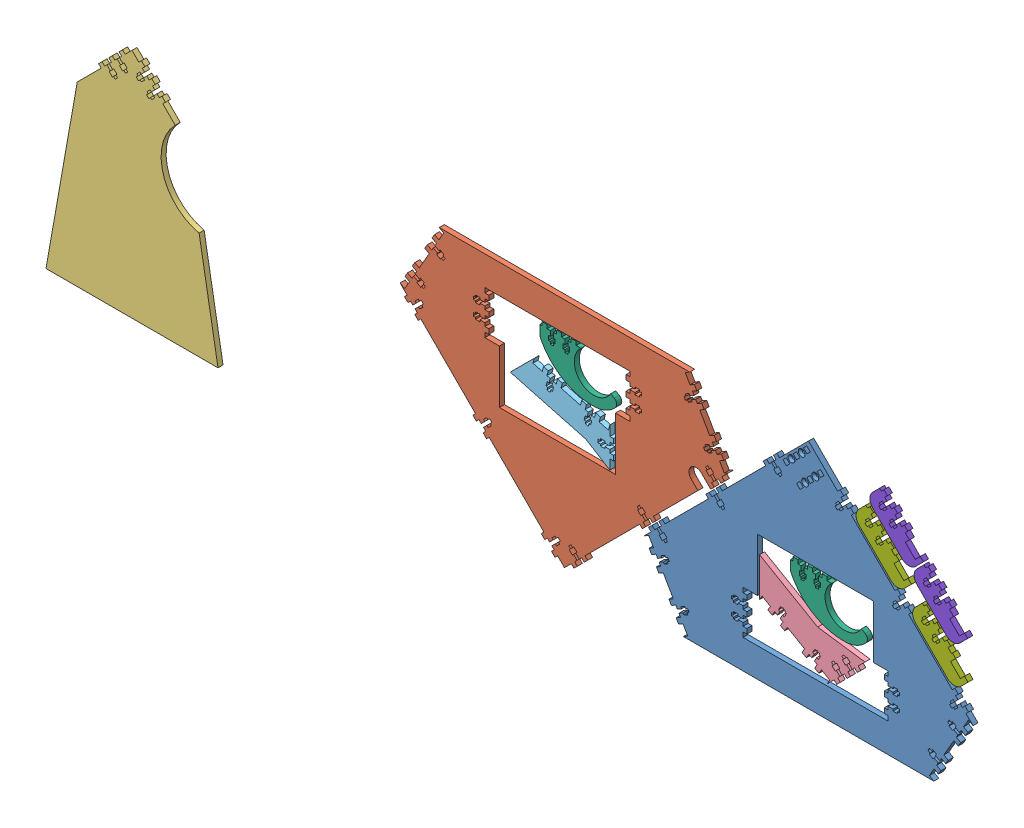
SolidWorks assembly Acrylic_1, configuration Default. Lengths in mm.
Overall size (1219.2 304.8 6.6).
11 component instances, 8 part files, 31 mates.
Components (placement in the parent):
- RIB 1, FRAME-1: RIB 1, FRAME [LASER CUT] at (-137.0148 0.0508 0) size (431.67 304.55 6.6)
- RIB 2, FRAME-1: RIB 2, FRAME [LASER CUT] at (-457.4769 304.7492 0) x (-1 0 0) z (0 0 1) size (431.67 304.55 6.6)
- RIB 3, FRAME-1: RIB 3, FRAME [LASER CUT] at (-1025.2225 0.0508 0) size (225.83 304.55 6.6)
- RIB 4 INFEED, FRAME-1: RIB 4 INFEED, FRAME [LASER CUT] at (-201.3286 256.3325 0) x (0 -1 0) z (0 0 1) size (102.28 138.45 6.6)
- RIB 4 OUTFEED, FRAME-1: RIB 4 OUTFEED, FRAME [LASER CUT] at (-613.2509 102.3228 0) x (-0.707107 -0.707107 0) z (0 0 1) size (96.17 124.97 6.6)
- BRACKET, VACUUM TUBE-1: BRACKET, VACUUM TUBE [LASER CUT] at (-435.898 265.5316 0) size (101.09 62.36 6.6)
- BRACKET, VACUUM TUBE-2: BRACKET, VACUUM TUBE [LASER CUT] at (-106.7136 162.7632 0) size (101.09 62.36 6.6)
- BRACKET, SCANNER BAR INFEED-1: BRACKET, SCANNER BAR INFEED [LASER CUT] at (-13.308 223.121 0) x (0.707107 -0.707107 0) z (0 0 1) size (84.81 30.33 6.6)
- BRACKET, SCANNER BAR INFEED-2: BRACKET, SCANNER BAR INFEED [LASER CUT] at (60.9152 148.8978 0) x (0.707107 -0.707107 0) z (0 0 1) size (84.81 30.33 6.6)
- BRACKET, SCANNER BAR OUTFEED-1: BRACKET, SCANNER BAR OUTFEED [LASER CUT] at (62.8947 193.4001 0) x (0.707107 -0.707107 0) z (0 0 1) size (79.6 30.33 6.6)
- BRACKET, SCANNER BAR OUTFEED-2: BRACKET, SCANNER BAR OUTFEED [LASER CUT] at (4.8104 251.4844 0) x (0.707107 -0.707107 0) z (0 0 1) size (79.6 30.33 6.6)
Mates (geometry in assembly coordinates):
- Coincident1: coincident aligned: plane of RIB 1, FRAME-1 through (-137.0148 0.0508 0) normal (0 0 -1); plane of RIB 2, FRAME-1 through (-457.4769 304.7492 0) normal (0 0 -1)
- Coincident5: coincident: line of RIB 1, FRAME-1 through (-301.4041 0 0) axis (1 0 0); plane of assembly
- Coincident3: coincident anti-aligned: plane of RIB 1, FRAME-1 through (-137.0148 0.0508 0) normal (0 0 -1); plane of assembly through (0 0 0) normal (0 0 1)
- Distance3: distance = 304.8 mm: line of RIB 2, FRAME-1 through (-293.0876 304.8 0) axis (-1 0 0); plane of assembly
- Distance4: distance = 11.43 mm: line of RIB 2, FRAME-1 through (-340.6617 117.0664 0) axis (0.707107 0.707107 0); line of RIB 1, FRAME-1 through (-268.4229 173.1407 0) axis (-0.707107 -0.707107 0)
- Coincident7: coincident aligned: plane of RIB 2, FRAME-1 through (-457.4769 304.7492 0) normal (0 0 -1); plane of RIB 3, FRAME-1 through (-1025.2225 0.0508 0) normal (0 0 -1)
- Coincident8: coincident aligned: plane of RIB 1, FRAME-1 through (27.1849 0 6.604) normal (0 -1 0); plane of RIB 3, FRAME-1 through (-912.3696 0 6.604) normal (0 -1 0)
- Distance5: distance = 271.78 mm: line of RIB 3, FRAME-1 through (-968.452 247.7782 6.604) axis (0 0 -1); plane of RIB 2, FRAME-1 through (-657.172 243.3709 -11.176) normal (-0.866025 0.5 0)
- Coincident10: coincident aligned: plane of RIB 1, FRAME-1 through (-137.0148 0.0508 0) normal (0 0 -1); plane of RIB 4 INFEED, FRAME-1 through (-201.3286 256.3325 0) normal (0 0 -1)
- Distance7: distance = 2.54 mm anti-aligned: plane of RIB 1, FRAME-1 through (-203.9194 165.1508 0) normal (1 0 0); plane of RIB 4 INFEED, FRAME-1 through (-201.3794 92.1328 6.604) normal (-1 0 0)
- Distance8: distance = 2.54 mm: plane of RIB 1, FRAME-1 through (-51.5702 38.2016 0) normal (0 1 0); moEndPointRef_w of RIB 4 INFEED, FRAME-1
- Coincident15: coincident aligned: plane of RIB 1, FRAME-1 through (-137.0148 0.0508 0) normal (0 0 -1); plane of RIB 4 OUTFEED, FRAME-1 through (-613.2509 102.3228 0) normal (0 0 -1)
- Distance10: distance = 2.54 mm: line of RIB 4 OUTFEED, FRAME-1 through (-393.1123 172.7602 0) axis (0 1 0); line of RIB 2, FRAME-1 through (-390.5723 139.7 0) axis (0 1 0)
- Distance11: distance = 1.27 mm: line of RIB 4 OUTFEED, FRAME-1 through (-397.9383 140.97 0) axis (0 0 1); plane of RIB 2, FRAME-1 through (-390.5215 139.7 0) normal (0 1 0)
- Coincident22: coincident aligned: plane of RIB 1, FRAME-1 through (-137.0148 0.0508 0) normal (0 0 -1); plane of BRACKET, VACUUM TUBE-2 through (-106.7136 162.7632 0) normal (0 0 -1)
- Coincident23: coincident aligned: plane of RIB 1, FRAME-1 through (-137.0148 0.0508 0) normal (0 0 -1); plane of BRACKET, VACUUM TUBE-1 through (-435.898 265.5316 0) normal (0 0 -1)
- Distance13: distance = 1.27 mm anti-aligned: plane of RIB 2, FRAME-1 through (-542.9215 266.5984 0) normal (0 -1 0); plane of BRACKET, VACUUM TUBE-1 through (-480.348 265.3284 -7.9758) normal (0 1 0)
- Distance15: distance = 2.54 mm anti-aligned: plane of RIB 1, FRAME-1 through (-203.9702 165.1 0) normal (0 -1 0); plane of BRACKET, VACUUM TUBE-2 through (-151.1636 162.56 -7.9758) normal (0 1 0)
- Distance16: distance = 43.18 mm anti-aligned: plane of BRACKET, VACUUM TUBE-2 through (-160.7394 162.7632 6.604) normal (-1 0 0); plane of RIB 1, FRAME-1 through (-203.9194 165.1508 0) normal (1 0 0)
- Coincident28: coincident aligned: plane of RIB 1, FRAME-1 through (-137.0148 0.0508 0) normal (0 0 -1); plane of BRACKET, SCANNER BAR INFEED-2 through (60.9152 148.8978 0) normal (0 0 -1)
- Coincident29: coincident aligned: plane of RIB 1, FRAME-1 through (-137.0148 0.0508 0) normal (0 0 -1); plane of BRACKET, SCANNER BAR INFEED-1 through (-13.308 223.121 0) normal (0 0 -1)
- Coincident30: coincident aligned: plane of RIB 1, FRAME-1 through (-137.0148 0.0508 0) normal (0 0 -1); plane of BRACKET, SCANNER BAR OUTFEED-1 through (62.8947 193.4001 0) normal (0 0 -1)
- Coincident31: coincident aligned: plane of RIB 1, FRAME-1 through (-137.0148 0.0508 0) normal (0 0 -1); plane of BRACKET, SCANNER BAR OUTFEED-2 through (4.8104 251.4844 0) normal (0 0 -1)
- Distance17: distance = 2.54 mm anti-aligned: plane of RIB 1, FRAME-1 through (-136.9789 304.5129 6.604) normal (0.707107 0.707107 0); plane of BRACKET, SCANNER BAR INFEED-2 through (-5.6644 176.7905 6.604) normal (-0.707107 -0.707107 0)
- Distance18: distance = 1.778 mm: line of RIB 1, FRAME-1 through (-2.1942 176.5532 0) axis (0 0 1); cylinder of BRACKET, SCANNER BAR INFEED-2 through (12.332 176.8264 6.604) axis (0 0 -1) radius 12.7508
- Distance19: distance = 2.54 mm anti-aligned: plane of RIB 1, FRAME-1 through (-136.9789 304.5129 6.604) normal (0.707107 0.707107 0); plane of BRACKET, SCANNER BAR INFEED-1 through (-79.8876 251.0137 6.604) normal (-0.707107 -0.707107 0)
- Distance20: distance = 1.778 mm: cylinder of BRACKET, SCANNER BAR INFEED-1 through (-19.9534 209.1118 6.604) axis (0 0 -1) radius 12.7508; line of RIB 1, FRAME-1 through (-20.2266 194.5856 0) axis (0 0 1)
- Distance21: distance = 2.54 mm anti-aligned: plane of BRACKET, SCANNER BAR OUTFEED-1 through (-3.6849 221.2928 6.604) normal (-0.707107 -0.707107 0); plane of BRACKET, SCANNER BAR INFEED-1 through (-42.7273 256.7431 -7.9758) normal (0.707107 0.707107 0)
- Distance22: distance = 20.32 mm: cylinder of BRACKET, SCANNER BAR OUTFEED-1 through (14.3115 221.3287 6.604) axis (0 0 -1) radius 12.7508; line of BRACKET, SCANNER BAR INFEED-1 through (-18.0855 227.9703 6.604) axis (0 0 -1)
- Coincident39: coincident aligned: plane of BRACKET, SCANNER BAR OUTFEED-1 through (-3.6849 221.2928 6.604) normal (-0.707107 -0.707107 0); plane of BRACKET, SCANNER BAR OUTFEED-2 through (-61.7692 279.3771 6.604) normal (-0.707107 -0.707107 0)
- Distance23: distance = 2.54 mm anti-aligned: plane of BRACKET, SCANNER BAR OUTFEED-2 through (13.8266 242.4682 6.604) normal (0.707107 -0.707107 0); plane of BRACKET, SCANNER BAR OUTFEED-1 through (14.2756 239.3251 6.604) normal (-0.707107 0.707107 0)
